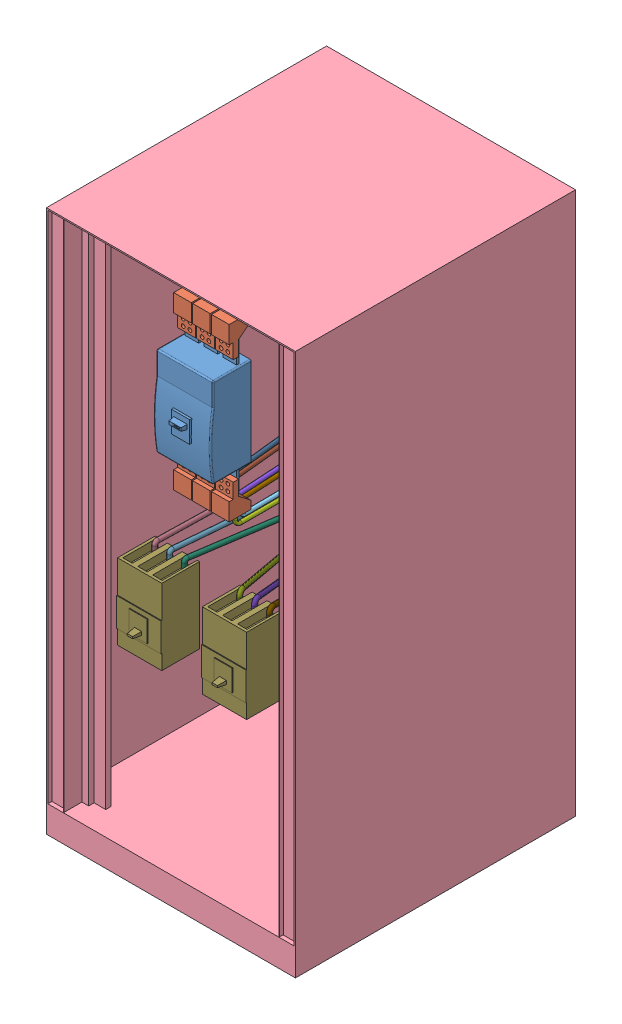
SolidWorks assembly Ensamble tablero de ditribución, configuration Predeterminado. Lengths in mm.
Overall size (920 2005 1035).
41 component instances, 19 part files, 127 mates.
Components (placement in the parent):
- INTERRUPTOR DE 1000 AMP-1: INTERRUPTOR DE 1000 AMP [Predeterminado] at (-1201.779 1141.3984 2879.7748) size (210 494 177)
- zapata interup 1000 amp-1: zapata interup 1000 amp [Predeterminado] at (-1271.779 1397.3984 2878.2748) size (65 120 80)
- zapata interup 1000 amp-2: zapata interup 1000 amp [Predeterminado] at (-1201.779 1397.3984 2878.2748) size (65 120 80)
- zapata interup 1000 amp-3: zapata interup 1000 amp [Predeterminado] at (-1131.779 1397.3984 2878.2748) size (65 120 80)
- zapata interup 1000 amp-7: zapata interup 1000 amp [Predeterminado] at (-1271.779 885.3984 2878.2748) x (-1 0 0) z (0 0 1) size (65 120 80)
- zapata interup 1000 amp-8: zapata interup 1000 amp [Predeterminado] at (-1201.779 885.3984 2878.2748) x (-1 0 0) z (0 0 1) size (65 120 80)
- zapata interup 1000 amp-9: zapata interup 1000 amp [Predeterminado] at (-1131.779 885.3984 2878.2748) x (-1 0 0) z (0 0 1) size (65 120 80)
- BARRA DE COBRE-4: BARRA DE COBRE [Predeterminado] at (-1307.279 325.3984 2071.2616) x (0 0 1) z (0 1 0) size (50.8 6 500)
- BARRA DE COBRE-5: BARRA DE COBRE [Predeterminado] at (-1201.779 825.3984 2071.2616) x (0 0 -1) z (0 -1 0) size (50.8 6 500)
- BARRA DE COBRE-6: BARRA DE COBRE [Predeterminado] at (-1096.279 825.3984 2071.2616) x (0 0 -1) z (0 -1 0) size (50.8 6 500)
- zapata interup 1000 amp-10: zapata interup 1000 amp [Predeterminado] at (-1375.279 792.8984 2105.8616) x (0 1 0) z (1 0 0) size (65 120 80)
- zapata interup 1000 amp-11: zapata interup 1000 amp [Predeterminado] at (-1269.779 792.8984 2105.8616) x (0 1 0) z (1 0 0) size (65 120 80)
- zapata interup 1000 amp-12: zapata interup 1000 amp [Predeterminado] at (-1164.279 792.8984 2105.8616) x (0 1 0) z (1 0 0) size (65 120 80)
- TABLERO DE D. 15-5-19-1: TABLERO DE D. 15-5-19 [Predeterminado] at (-1201.779 603.8984 2035.8616) size (920 2005 1035)
- Pieza5^Ensamble tablero de ditribución-1: Pieza5^Ensamble tablero de ditribución [Predeterminado] at (-1131.779 825.3984 2878.2748) x (-1 0 0) z (0 -1 0) size (20.5 735.48 26.98) (virtual)
- CABLE INTERRUP 1000-1: CABLE INTERRUP 1000 [Predeterminado] at (-1285.779 1597.3984 2894.2748) x (0.998379 0 0.056922) z (0 -1 0) size (18 18 140)
- CABLE INTERRUP 1000-2: CABLE INTERRUP 1000 [Predeterminado] at (-1257.779 1597.3984 2894.2748) x (0.733767 0 0.679401) z (0 -1 0) size (18 18 140)
- CABLE INTERRUP 1000-3: CABLE INTERRUP 1000 [Predeterminado] at (-1215.779 1597.3984 2894.2748) x (1 0 0) z (0 -1 0) size (18 18 140)
- CABLE INTERRUP 1000-4: CABLE INTERRUP 1000 [Predeterminado] at (-1187.779 1597.3984 2894.2748) x (1 0 0) z (0 -1 0) size (18 18 140)
- CABLE INTERRUP 1000-5: CABLE INTERRUP 1000 [Predeterminado] at (-1145.779 1597.3984 2894.2748) x (0.945572 0 0.325412) z (0 -1 0) size (18 18 140)
- CABLE INTERRUP 1000-6: CABLE INTERRUP 1000 [Predeterminado] at (-1117.779 1597.3984 2894.2748) x (1 0 0) z (0 -1 0) size (18 18 140)
- Pieza10^Ensamble tablero de ditribución-1: Pieza10^Ensamble tablero de ditribución [Predeterminado] at (-1131.779 825.3984 2878.2748) x (-1 0 0) z (0 -1 0) size (20.5 759.5 53.5) (virtual)
- Pieza11^Ensamble tablero de ditribución-1: Pieza11^Ensamble tablero de ditribución [Predeterminado] at (-1201.779 825.3984 2878.2748) x (-1 0 0) z (0 -1 0) size (55.99 735.82 26.98) (virtual)
- Pieza12^Ensamble tablero de ditribución-1: Pieza12^Ensamble tablero de ditribución [Predeterminado] at (-1201.779 825.3984 2878.2748) x (-1 0 0) z (0 -1 0) size (55.99 759.81 53.5) (virtual)
- Pieza13^Ensamble tablero de ditribución-1: Pieza13^Ensamble tablero de ditribución [Predeterminado] at (-1271.779 825.3984 2878.2748) x (-1 0 0) z (0 -1 0) size (91.46 736.15 26.98) (virtual)
- Pieza15^Ensamble tablero de ditribución-1: Pieza15^Ensamble tablero de ditribución [Predeterminado] at (-1271.779 825.3984 2878.2748) x (-1 0 0) z (0 -1 0) size (91.46 760.13 53.5) (virtual)
- INTERRUPTOR DE BAJA-1: INTERRUPTOR DE BAJA [Predeterminado] at (-1276.779 436.6484 2960.2748) x (0 0 1) z (-1 0 0) size (175 279.5 163.5)
- INTERRUPTOR DE BAJA-3: INTERRUPTOR DE BAJA [Predeterminado] at (-963.279 436.6484 2960.2748) x (0 0 1) z (-1 0 0) size (175 279.5 163.5)
- zapata interup 1000 amp-19: zapata interup 1000 amp [Predeterminado] at (-1375.279 607.8984 2105.8616) x (0 1 0) z (1 0 0) size (65 120 80)
- zapata interup 1000 amp-20: zapata interup 1000 amp [Predeterminado] at (-1269.779 607.8984 2105.8616) x (0 1 0) z (1 0 0) size (65 120 80)
- zapata interup 1000 amp-21: zapata interup 1000 amp [Predeterminado] at (-1164.279 607.8984 2105.8616) x (0 1 0) z (1 0 0) size (65 120 80)
- zapata interup 1000 amp-22: zapata interup 1000 amp [Predeterminado] at (-1375.279 422.8984 2105.8616) x (0 1 0) z (1 0 0) size (65 120 80)
- zapata interup 1000 amp-23: zapata interup 1000 amp [Predeterminado] at (-1269.779 422.8984 2105.8616) x (0 1 0) z (1 0 0) size (65 120 80)
- zapata interup 1000 amp-24: zapata interup 1000 amp [Predeterminado] at (-1164.279 422.8984 2105.8616) x (0 1 0) z (1 0 0) size (65 120 80)
- Pieza19^Ensamble tablero de ditribución-1: Pieza19^Ensamble tablero de ditribución [Predeterminado] at (-1276.779 546.3984 2960.2748) x (0 0 1) z (0 1 0) size (762.47 69.48 83.49) (virtual)
- Pieza21^Ensamble tablero de ditribución-1: Pieza21^Ensamble tablero de ditribución [Predeterminado] at (-1276.779 546.3984 2960.2748) x (0 0 1) z (0 1 0) (virtual)
- Pieza22^Ensamble tablero de ditribución-1: Pieza22^Ensamble tablero de ditribución [Predeterminado] at (-1276.779 546.3984 2960.2748) x (0 0 1) z (0 1 0) size (762.95 119.93 83.49) (virtual)
- Pieza23^Ensamble tablero de ditribución-1: Pieza23^Ensamble tablero de ditribución [Predeterminado] at (-1276.779 546.3984 2960.2748) x (0 0 1) z (0 1 0) size (763.44 170.34 83.49) (virtual)
- Pieza24^Ensamble tablero de ditribución-1: Pieza24^Ensamble tablero de ditribución [Predeterminado] at (-963.279 546.3984 2960.2748) x (0 0 1) z (0 1 0) size (764.75 275.58 162.29) (virtual)
- Pieza25^Ensamble tablero de ditribución-1: Pieza25^Ensamble tablero de ditribución [Predeterminado] at (-963.279 546.3984 2960.2748) x (0 0 1) z (0 1 0) size (764.38 225.22 162.22) (virtual)
- Pieza26^Ensamble tablero de ditribución-1: Pieza26^Ensamble tablero de ditribución [Predeterminado] at (-963.279 546.3984 2960.2748) x (0 0 1) z (0 1 0) size (764.02 174.83 162.16) (virtual)
Mates (geometry in assembly coordinates):
- Coincidente4: coincident anti-aligned: plane of INTERRUPTOR DE 1000 AMP-1 through (-1014.3897 1388.3984 2923.2748) normal (0 0 1); plane of zapata interup 1000 amp-1 through (-1319.279 1337.3984 2923.2748) normal (0 0 -1)
- Concéntrica1: concentric aligned: cylinder of INTERRUPTOR DE 1000 AMP-1 through (-1284.279 1352.3984 2895.4758) axis (0 0 1) radius 7; cylinder of zapata interup 1000 amp-1 through (-1284.279 1352.3984 2903.4758) axis (0 0 1) radius 7
- Coincidente5: coincident anti-aligned: plane of INTERRUPTOR DE 1000 AMP-1 through (-1014.3897 1388.3984 2923.2748) normal (0 0 1); plane of zapata interup 1000 amp-2 through (-1249.279 1337.3984 2923.2748) normal (0 0 -1)
- Concéntrica2: concentric aligned: cylinder of INTERRUPTOR DE 1000 AMP-1 through (-1189.279 1352.3984 2895.4758) axis (0 0 1) radius 7; cylinder of zapata interup 1000 amp-2 through (-1189.279 1352.3984 2903.4758) axis (0 0 1) radius 7
- Coincidente6: coincident anti-aligned: plane of INTERRUPTOR DE 1000 AMP-1 through (-1014.3897 1388.3984 2923.2748) normal (0 0 1); plane of zapata interup 1000 amp-3 through (-1179.279 1337.3984 2923.2748) normal (0 0 -1)
- Concéntrica4: concentric aligned: cylinder of INTERRUPTOR DE 1000 AMP-1 through (-1144.279 1352.3984 2895.4758) axis (0 0 1) radius 7; cylinder of zapata interup 1000 amp-3 through (-1144.279 1352.3984 2903.4758) axis (0 0 1) radius 7
- Coincidente8: coincident anti-aligned: plane of INTERRUPTOR DE 1000 AMP-1 through (-1014.3897 894.3984 2923.2748) normal (0 0 1); plane of zapata interup 1000 amp-9 through (-1084.279 945.3984 2923.2748) normal (0 0 -1)
- Ancho3: width aligned: plane of zapata interup 1000 amp-9 through (-1099.279 945.3984 2958.2748) normal (1 0 0); plane of zapata interup 1000 amp-9 through (-1164.279 945.3984 2958.2748) normal (-1 0 0); plane of INTERRUPTOR DE 1000 AMP-1 through (-1106.779 976.3984 2830.871) normal (1 0 0); plane of INTERRUPTOR DE 1000 AMP-1 through (-1156.779 976.3984 2830.871) normal (-1 0 0)
- Concéntrica5: concentric aligned: cylinder of INTERRUPTOR DE 1000 AMP-1 through (-1119.279 906.3984 2894.6673) axis (0 0 1) radius 7; cylinder of zapata interup 1000 amp-9 through (-1119.279 906.3984 2903.4758) axis (0 0 1) radius 7
- Coincidente10: coincident anti-aligned: plane of INTERRUPTOR DE 1000 AMP-1 through (-1014.3897 894.3984 2923.2748) normal (0 0 1); plane of zapata interup 1000 amp-8 through (-1154.279 945.3984 2923.2748) normal (0 0 -1)
- Ancho4: width aligned: plane of zapata interup 1000 amp-8 through (-1169.279 945.3984 2958.2748) normal (1 0 0); plane of zapata interup 1000 amp-8 through (-1234.279 945.3984 2958.2748) normal (-1 0 0); plane of INTERRUPTOR DE 1000 AMP-1 through (-1176.779 976.3984 2830.871) normal (1 0 0); plane of INTERRUPTOR DE 1000 AMP-1 through (-1226.779 976.3984 2830.871) normal (-1 0 0)
- Coincidente11: coincident anti-aligned: plane of INTERRUPTOR DE 1000 AMP-1 through (-1014.3897 894.3984 2923.2748) normal (0 0 1); plane of zapata interup 1000 amp-7 through (-1224.279 945.3984 2923.2748) normal (0 0 -1)
- Ancho5: width aligned: plane of zapata interup 1000 amp-7 through (-1304.279 945.3984 2958.2748) normal (-1 0 0); plane of zapata interup 1000 amp-7 through (-1239.279 945.3984 2958.2748) normal (1 0 0); plane of INTERRUPTOR DE 1000 AMP-1 through (-1296.779 976.3984 2830.871) normal (-1 0 0); plane of INTERRUPTOR DE 1000 AMP-1 through (-1246.779 976.3984 2830.871) normal (1 0 0)
- Concéntrica6: concentric aligned: cylinder of INTERRUPTOR DE 1000 AMP-1 through (-1214.279 906.3984 2894.6673) axis (0 0 1) radius 7; cylinder of zapata interup 1000 amp-8 through (-1214.279 906.3984 2903.4758) axis (0 0 1) radius 7
- Concéntrica7: concentric aligned: cylinder of INTERRUPTOR DE 1000 AMP-1 through (-1259.279 906.3984 2894.6673) axis (0 0 1) radius 7; cylinder of zapata interup 1000 amp-7 through (-1259.279 906.3984 2903.4758) axis (0 0 1) radius 7
- Coincidente21: coincident aligned: plane of BARRA DE COBRE-4 through (-1304.279 825.3984 2045.8616) normal (0 0 -1); plane of BARRA DE COBRE-5 through (-1198.779 325.3984 2045.8616) normal (0 0 -1)
- Coincidente22: coincident anti-aligned: plane of zapata interup 1000 amp-7 through (-1239.279 825.3984 2958.2748) normal (0 -1 0); plane of BARRA DE COBRE-4 through (-1307.279 825.3984 2071.2616) normal (0 1 0)
- Coincidente23: coincident aligned: plane of BARRA DE COBRE-4 through (-1307.279 825.3984 2071.2616) normal (0 1 0); plane of BARRA DE COBRE-5 through (-1201.779 825.3984 2071.2616) normal (0 1 0)
- Coincidente24: coincident aligned: plane of BARRA DE COBRE-5 through (-1198.779 325.3984 2045.8616) normal (0 0 -1); plane of BARRA DE COBRE-6 through (-1093.279 325.3984 2045.8616) normal (0 0 -1)
- Coincidente25: coincident aligned: plane of BARRA DE COBRE-5 through (-1201.779 825.3984 2071.2616) normal (0 1 0); plane of BARRA DE COBRE-6 through (-1096.279 825.3984 2071.2616) normal (0 1 0)
- Coincidente26: coincident anti-aligned: plane of BARRA DE COBRE-4 through (-1310.279 825.3984 2045.8616) normal (-1 0 0); plane of zapata interup 1000 amp-10 through (-1310.279 745.3984 2100.8616) normal (1 0 0)
- Coincidente27: coincident aligned: plane of BARRA DE COBRE-4 through (-1304.279 825.3984 2045.8616) normal (0 0 -1); plane of zapata interup 1000 amp-10 through (-1295.279 760.3984 2045.8616) normal (0 0 -1)
- Coincidente28: coincident aligned: plane of BARRA DE COBRE-4 through (-1307.279 825.3984 2071.2616) normal (0 1 0); plane of zapata interup 1000 amp-10 through (-1295.279 825.3984 2045.8616) normal (0 1 0)
- Coincidente29: coincident anti-aligned: plane of zapata interup 1000 amp-7 through (-1304.279 945.3984 2958.2748) normal (-1 0 0); plane of BARRA DE COBRE-4 through (-1304.279 825.3984 2045.8616) normal (1 0 0)
- Coincidente30: coincident anti-aligned: plane of zapata interup 1000 amp-9 through (-1099.279 945.3984 2958.2748) normal (1 0 0); plane of BARRA DE COBRE-6 through (-1099.279 325.3984 2096.6616) normal (-1 0 0)
- Ancho12: width anti-aligned: plane of zapata interup 1000 amp-8 through (-1169.279 945.3984 2958.2748) normal (1 0 0); plane of zapata interup 1000 amp-8 through (-1234.279 945.3984 2958.2748) normal (-1 0 0); plane of BARRA DE COBRE-5 through (-1204.779 325.3984 2096.6616) normal (-1 0 0); plane of BARRA DE COBRE-5 through (-1198.779 325.3984 2096.6616) normal (1 0 0)
- Coincidente31: coincident anti-aligned: plane of BARRA DE COBRE-5 through (-1204.779 325.3984 2096.6616) normal (-1 0 0); plane of zapata interup 1000 amp-11 through (-1204.779 745.3984 2100.8616) normal (1 0 0)
- Coincidente32: coincident aligned: plane of BARRA DE COBRE-5 through (-1201.779 825.3984 2071.2616) normal (0 1 0); plane of zapata interup 1000 amp-11 through (-1189.779 825.3984 2045.8616) normal (0 1 0)
- Coincidente33: coincident aligned: plane of BARRA DE COBRE-5 through (-1198.779 325.3984 2045.8616) normal (0 0 -1); plane of zapata interup 1000 amp-11 through (-1189.779 760.3984 2045.8616) normal (0 0 -1)
- Coincidente34: coincident anti-aligned: plane of BARRA DE COBRE-6 through (-1099.279 325.3984 2096.6616) normal (-1 0 0); plane of zapata interup 1000 amp-12 through (-1099.279 745.3984 2100.8616) normal (1 0 0)
- Coincidente35: coincident aligned: plane of BARRA DE COBRE-6 through (-1093.279 325.3984 2045.8616) normal (0 0 -1); plane of zapata interup 1000 amp-12 through (-1084.279 760.3984 2045.8616) normal (0 0 -1)
- Coincidente36: coincident aligned: plane of BARRA DE COBRE-6 through (-1096.279 825.3984 2071.2616) normal (0 1 0); plane of zapata interup 1000 amp-12 through (-1084.279 825.3984 2045.8616) normal (0 1 0)
- Coincidente37: coincident aligned: plane of INTERRUPTOR DE 1000 AMP-1 through (-1201.779 1141.3984 3055.7748) normal (0 0 1); plane of TABLERO DE D. 15-5-19-1 through (-1601.779 1679.1188 3055.7748) normal (0 0 1)
- Ancho13: width aligned: plane of TABLERO DE D. 15-5-19-1 through (-1661.779 -398.6016 3070.8616) normal (-1 0 0); plane of TABLERO DE D. 15-5-19-1 through (-741.779 -398.6016 3070.8616) normal (1 0 0); plane of INTERRUPTOR DE 1000 AMP-1 through (-1306.779 976.3984 3029.7748) normal (-1 0 0); plane of INTERRUPTOR DE 1000 AMP-1 through (-1096.779 976.3984 3029.7748) normal (1 0 0)
- Distancia4: distance = 300 mm aligned: plane of TABLERO DE D. 15-5-19-1 through (-1661.779 1606.3984 3070.8616) normal (0 1 0); plane of INTERRUPTOR DE 1000 AMP-1 through (-1306.779 1306.3984 3029.7748) normal (0 1 0)
- Coincidente39: coincident anti-aligned: plane of BARRA DE COBRE-6 through (-1093.279 325.3984 2045.8616) normal (0 0 -1); plane of TABLERO DE D. 15-5-19-1 through (-1201.779 603.8984 2045.8616) normal (0 0 1)
- EnPosición3: in place: plane of zapata interup 1000 amp-9 through (-1099.279 825.3984 2958.2748) normal (0 -1 0); plane of ? through (0 825.3984 0) normal (0 -1 0); moOrthogonalPlaneRef_w of zapata interup 1000 amp-9 through (-1099.279 825.3984 2958.2748) normal (0 -1 0); unknown of ?; plane of zapata interup 1000 amp-9 through (-1099.279 825.3984 2958.2748) normal (0 -1 0); line of ? through (-55 0 825.3984) axis (0 -1 0); plane of zapata interup 1000 amp-9 through (-1099.279 825.3984 2958.2748) normal (0 -1 0); unknown of ?
- Coincidente53: coincident aligned: plane of zapata interup 1000 amp-9; plane of Pieza5^Ensamble tablero de ditribución-1
- Coincidente54: coincident aligned: moOrthogonalPlaneRef_w of zapata interup 1000 amp-9 through (-1131.779 825.3984 2878.2748) normal (0 0 -1); plane of Pieza5^Ensamble tablero de ditribución-1
- Coincidente55: coincident anti-aligned: moOrthogonalPlaneRef_w of zapata interup 1000 amp-9 through (-1131.779 825.3984 2878.2748) normal (1 0 0); plane of Pieza5^Ensamble tablero de ditribución-1
- Concéntrica8: concentric aligned: cylinder of zapata interup 1000 amp-1 through (-1285.779 1447.3984 2894.2748) axis (0 1 0) radius 7; cylinder of CABLE INTERRUP 1000-1 through (-1285.779 1457.3984 2894.2748) axis (0 1 0) radius 9
- Paralelo1: parallel aligned: plane of INTERRUPTOR DE 1000 AMP-1 through (-1296.779 1388.3984 2830.871) normal (-1 0 0); plane of zapata interup 1000 amp-1 through (-1304.279 1337.3984 2958.2748) normal (-1 0 0)
- Coincidente65: coincident anti-aligned: plane of zapata interup 1000 amp-1 through (-1304.279 1457.3984 2958.2748) normal (0 1 0); plane of CABLE INTERRUP 1000-1 through (-1285.779 1457.3984 2894.2748) normal (0 -1 0)
- Concéntrica9: concentric aligned: cylinder of zapata interup 1000 amp-1 through (-1257.779 1447.3984 2894.2748) axis (0 1 0) radius 7; cylinder of CABLE INTERRUP 1000-2 through (-1257.779 1457.3984 2894.2748) axis (0 1 0) radius 9
- Coincidente66: coincident anti-aligned: plane of zapata interup 1000 amp-1 through (-1304.279 1457.3984 2958.2748) normal (0 1 0); plane of CABLE INTERRUP 1000-2 through (-1257.779 1457.3984 2894.2748) normal (0 -1 0)
- Concéntrica10: concentric aligned: cylinder of zapata interup 1000 amp-2 through (-1215.779 1447.3984 2894.2748) axis (0 1 0) radius 7; cylinder of CABLE INTERRUP 1000-3 through (-1215.779 1457.3984 2894.2748) axis (0 1 0) radius 9
- Coincidente67: coincident anti-aligned: plane of zapata interup 1000 amp-2 through (-1234.279 1457.3984 2958.2748) normal (0 1 0); plane of CABLE INTERRUP 1000-3 through (-1215.779 1457.3984 2894.2748) normal (0 -1 0)
- Concéntrica11: concentric aligned: cylinder of zapata interup 1000 amp-2 through (-1187.779 1447.3984 2894.2748) axis (0 1 0) radius 7; cylinder of CABLE INTERRUP 1000-4 through (-1187.779 1457.3984 2894.2748) axis (0 1 0) radius 9
- Coincidente68: coincident anti-aligned: plane of zapata interup 1000 amp-2 through (-1234.279 1457.3984 2958.2748) normal (0 1 0); plane of CABLE INTERRUP 1000-4 through (-1187.779 1457.3984 2894.2748) normal (0 -1 0)
- Concéntrica12: concentric aligned: cylinder of zapata interup 1000 amp-3 through (-1145.779 1447.3984 2894.2748) axis (0 1 0) radius 7; cylinder of CABLE INTERRUP 1000-5 through (-1145.779 1457.3984 2894.2748) axis (0 1 0) radius 9
- Paralelo2: parallel aligned: plane of INTERRUPTOR DE 1000 AMP-1 through (-1106.779 1306.3984 2830.871) normal (1 0 0); plane of zapata interup 1000 amp-3 through (-1099.279 1337.3984 2958.2748) normal (1 0 0)
- Coincidente69: coincident anti-aligned: plane of zapata interup 1000 amp-3 through (-1164.279 1457.3984 2958.2748) normal (0 1 0); plane of CABLE INTERRUP 1000-5 through (-1145.779 1457.3984 2894.2748) normal (0 -1 0)
- Concéntrica13: concentric aligned: cylinder of zapata interup 1000 amp-3 through (-1117.779 1447.3984 2894.2748) axis (0 1 0) radius 7; cylinder of CABLE INTERRUP 1000-6 through (-1117.779 1457.3984 2894.2748) axis (0 1 0) radius 9
- Coincidente70: coincident anti-aligned: plane of zapata interup 1000 amp-3 through (-1164.279 1457.3984 2958.2748) normal (0 1 0); plane of CABLE INTERRUP 1000-6 through (-1117.779 1457.3984 2894.2748) normal (0 -1 0)
- EnPosición7: in place: plane of zapata interup 1000 amp-9 through (-1099.279 825.3984 2958.2748) normal (0 -1 0); plane of ? through (0 825.3984 0) normal (0 -1 0); plane of zapata interup 1000 amp-9 through (-1099.279 825.3984 2958.2748) normal (0 -1 0); unknown of ?; plane of zapata interup 1000 amp-9 through (-1099.279 825.3984 2958.2748) normal (0 -1 0); line of ? through (-55 0 825.3984) axis (0 -1 0); plane of zapata interup 1000 amp-9 through (-1099.279 825.3984 2958.2748) normal (0 -1 0); unknown of ?
- Coincidente71: coincident aligned: plane of zapata interup 1000 amp-9; plane of Pieza10^Ensamble tablero de ditribución-1
- Coincidente72: coincident aligned: moOrthogonalPlaneRef_w of zapata interup 1000 amp-9 through (-1131.779 825.3984 2878.2748) normal (0 0 -1); plane of Pieza10^Ensamble tablero de ditribución-1
- Coincidente73: coincident anti-aligned: moOrthogonalPlaneRef_w of zapata interup 1000 amp-9 through (-1131.779 825.3984 2878.2748) normal (1 0 0); plane of Pieza10^Ensamble tablero de ditribución-1
- EnPosición8: in place: plane of zapata interup 1000 amp-8 through (-1169.279 825.3984 2958.2748) normal (0 -1 0); plane of ? through (0 825.3984 0) normal (0 -1 0); plane of zapata interup 1000 amp-8 through (-1169.279 825.3984 2958.2748) normal (0 -1 0); unknown of ?; plane of zapata interup 1000 amp-8 through (-1169.279 825.3984 2958.2748) normal (0 -1 0); line of ? through (-55 0 825.3984) axis (0 -1 0); plane of zapata interup 1000 amp-8 through (-1169.279 825.3984 2958.2748) normal (0 -1 0); unknown of ?
- Coincidente74: coincident aligned: plane of zapata interup 1000 amp-8; plane of Pieza11^Ensamble tablero de ditribución-1
- Coincidente75: coincident aligned: moOrthogonalPlaneRef_w of zapata interup 1000 amp-8 through (-1201.779 825.3984 2878.2748) normal (0 0 -1); plane of Pieza11^Ensamble tablero de ditribución-1
- Coincidente76: coincident anti-aligned: moOrthogonalPlaneRef_w of zapata interup 1000 amp-8 through (-1201.779 825.3984 2878.2748) normal (1 0 0); plane of Pieza11^Ensamble tablero de ditribución-1
- EnPosición9: in place: plane of zapata interup 1000 amp-8 through (-1169.279 825.3984 2958.2748) normal (0 -1 0); plane of ? through (0 825.3984 0) normal (0 -1 0); plane of zapata interup 1000 amp-8 through (-1169.279 825.3984 2958.2748) normal (0 -1 0); unknown of ?; plane of zapata interup 1000 amp-8 through (-1169.279 825.3984 2958.2748) normal (0 -1 0); line of ? through (-55 0 825.3984) axis (0 -1 0); plane of zapata interup 1000 amp-8 through (-1169.279 825.3984 2958.2748) normal (0 -1 0); unknown of ?
- Coincidente77: coincident aligned: plane of zapata interup 1000 amp-8; plane of Pieza12^Ensamble tablero de ditribución-1
- Coincidente78: coincident aligned: moOrthogonalPlaneRef_w of zapata interup 1000 amp-8 through (-1201.779 825.3984 2878.2748) normal (0 0 -1); plane of Pieza12^Ensamble tablero de ditribución-1
- Coincidente79: coincident anti-aligned: moOrthogonalPlaneRef_w of zapata interup 1000 amp-8 through (-1201.779 825.3984 2878.2748) normal (1 0 0); plane of Pieza12^Ensamble tablero de ditribución-1
- EnPosición10: in place: plane of zapata interup 1000 amp-7 through (-1239.279 825.3984 2958.2748) normal (0 -1 0); plane of ? through (0 825.3984 0) normal (0 -1 0); plane of zapata interup 1000 amp-7 through (-1239.279 825.3984 2958.2748) normal (0 -1 0); unknown of ?; plane of zapata interup 1000 amp-7 through (-1239.279 825.3984 2958.2748) normal (0 -1 0); line of ? through (-55 0 825.3984) axis (0 -1 0); plane of zapata interup 1000 amp-7 through (-1239.279 825.3984 2958.2748) normal (0 -1 0); unknown of ?
- Coincidente80: coincident aligned: plane of zapata interup 1000 amp-7; plane of Pieza13^Ensamble tablero de ditribución-1
- Coincidente81: coincident aligned: moOrthogonalPlaneRef_w of zapata interup 1000 amp-7 through (-1271.779 825.3984 2878.2748) normal (0 0 -1); plane of Pieza13^Ensamble tablero de ditribución-1
- Coincidente82: coincident anti-aligned: moOrthogonalPlaneRef_w of zapata interup 1000 amp-7 through (-1271.779 825.3984 2878.2748) normal (1 0 0); plane of Pieza13^Ensamble tablero de ditribución-1
- EnPosición12: in place: plane of zapata interup 1000 amp-7 through (-1239.279 825.3984 2958.2748) normal (0 -1 0); plane of ? through (0 825.3984 0) normal (0 -1 0); plane of zapata interup 1000 amp-7 through (-1239.279 825.3984 2958.2748) normal (0 -1 0); unknown of ?; plane of zapata interup 1000 amp-7 through (-1239.279 825.3984 2958.2748) normal (0 -1 0); line of ? through (-55 0 825.3984) axis (0 -1 0); plane of zapata interup 1000 amp-7 through (-1239.279 825.3984 2958.2748) normal (0 -1 0); unknown of ?
- Coincidente86: coincident aligned: plane of zapata interup 1000 amp-7; plane of Pieza15^Ensamble tablero de ditribución-1
- Coincidente87: coincident aligned: moOrthogonalPlaneRef_w of zapata interup 1000 amp-7 through (-1271.779 825.3984 2878.2748) normal (0 0 -1); plane of Pieza15^Ensamble tablero de ditribución-1
- Coincidente88: coincident anti-aligned: moOrthogonalPlaneRef_w of zapata interup 1000 amp-7 through (-1271.779 825.3984 2878.2748) normal (1 0 0); plane of Pieza15^Ensamble tablero de ditribución-1
- Coincidente71: coincident aligned: plane of INTERRUPTOR DE 1000 AMP-1 through (-1201.779 1141.3984 3035.7748) normal (0 0 1); plane of INTERRUPTOR DE BAJA-1 through (-1276.779 436.6484 3035.7748) normal (0 0 1)
- Distancia5: distance = 400 mm anti-aligned: plane of INTERRUPTOR DE 1000 AMP-1 through (-1306.779 976.3984 3029.7748) normal (0 -1 0); plane of INTERRUPTOR DE BAJA-1 through (-1440.279 576.3984 2890.7748) normal (0 1 0)
- Distancia6: distance = 400 mm anti-aligned: plane of INTERRUPTOR DE 1000 AMP-1 through (-1306.779 976.3984 3029.7748) normal (0 -1 0); plane of INTERRUPTOR DE BAJA-3 through (-1126.779 576.3984 2890.7748) normal (0 1 0)
- Coincidente75: coincident aligned: plane of INTERRUPTOR DE BAJA-1 through (-1276.779 436.6484 3035.7748) normal (0 0 1); plane of INTERRUPTOR DE BAJA-3 through (-963.279 436.6484 3035.7748) normal (0 0 1)
- Distancia7: distance = 150 mm anti-aligned: plane of INTERRUPTOR DE BAJA-1 through (-1276.779 436.6484 2960.2748) normal (1 0 0); plane of INTERRUPTOR DE BAJA-3 through (-1126.779 436.6484 2960.2748) normal (-1 0 0)
- Ancho14: width anti-aligned: plane of TABLERO DE D. 15-5-19-1 through (-1531.279 1728.1511 2962.8616) normal (1 0 0); plane of TABLERO DE D. 15-5-19-1 through (-872.279 1728.1511 2962.8616) normal (-1 0 0); plane of INTERRUPTOR DE BAJA-1 through (-1440.279 436.6484 2960.2748) normal (-1 0 0); plane of INTERRUPTOR DE BAJA-3 through (-963.279 436.6484 2960.2748) normal (1 0 0)
- Distancia8: distance = 120 mm anti-aligned: plane of zapata interup 1000 amp-10 through (-1295.279 760.3984 2045.8616) normal (0 -1 0); plane of zapata interup 1000 amp-19 through (-1295.279 640.3984 2045.8616) normal (0 1 0)
- Coincidente78: coincident anti-aligned: plane of BARRA DE COBRE-4 through (-1310.279 825.3984 2045.8616) normal (-1 0 0); plane of zapata interup 1000 amp-19 through (-1310.279 560.3984 2100.8616) normal (1 0 0)
- Coincidente79: coincident aligned: plane of BARRA DE COBRE-4 through (-1304.279 825.3984 2045.8616) normal (0 0 -1); plane of zapata interup 1000 amp-19 through (-1295.279 575.3984 2045.8616) normal (0 0 -1)
- Coincidente80: coincident aligned: plane of zapata interup 1000 amp-19 through (-1295.279 640.3984 2045.8616) normal (0 1 0); plane of zapata interup 1000 amp-20 through (-1189.779 640.3984 2045.8616) normal (0 1 0)
- Coincidente81: coincident anti-aligned: plane of BARRA DE COBRE-5 through (-1204.779 325.3984 2096.6616) normal (-1 0 0); plane of zapata interup 1000 amp-20 through (-1204.779 560.3984 2100.8616) normal (1 0 0)
- Coincidente82: coincident aligned: plane of BARRA DE COBRE-5 through (-1198.779 325.3984 2045.8616) normal (0 0 -1); plane of zapata interup 1000 amp-20 through (-1189.779 575.3984 2045.8616) normal (0 0 -1)
- Coincidente83: coincident aligned: plane of zapata interup 1000 amp-20 through (-1189.779 640.3984 2045.8616) normal (0 1 0); plane of zapata interup 1000 amp-21 through (-1084.279 640.3984 2045.8616) normal (0 1 0)
- Coincidente84: coincident anti-aligned: plane of BARRA DE COBRE-6 through (-1099.279 325.3984 2096.6616) normal (-1 0 0); plane of zapata interup 1000 amp-21 through (-1099.279 560.3984 2100.8616) normal (1 0 0)
- Coincidente85: coincident aligned: plane of BARRA DE COBRE-6 through (-1093.279 325.3984 2045.8616) normal (0 0 -1); plane of zapata interup 1000 amp-21 through (-1084.279 575.3984 2045.8616) normal (0 0 -1)
- Distancia9: distance = 120 mm anti-aligned: plane of zapata interup 1000 amp-19 through (-1295.279 575.3984 2045.8616) normal (0 -1 0); plane of zapata interup 1000 amp-22 through (-1295.279 455.3984 2045.8616) normal (0 1 0)
- Coincidente87: coincident anti-aligned: plane of BARRA DE COBRE-4 through (-1310.279 825.3984 2045.8616) normal (-1 0 0); plane of zapata interup 1000 amp-22 through (-1310.279 375.3984 2100.8616) normal (1 0 0)
- Coincidente88: coincident aligned: plane of BARRA DE COBRE-4 through (-1304.279 825.3984 2045.8616) normal (0 0 -1); plane of zapata interup 1000 amp-22 through (-1295.279 390.3984 2045.8616) normal (0 0 -1)
- Coincidente89: coincident aligned: plane of zapata interup 1000 amp-22 through (-1295.279 455.3984 2045.8616) normal (0 1 0); plane of zapata interup 1000 amp-23 through (-1189.779 455.3984 2045.8616) normal (0 1 0)
- Coincidente90: coincident anti-aligned: plane of BARRA DE COBRE-5 through (-1204.779 325.3984 2096.6616) normal (-1 0 0); plane of zapata interup 1000 amp-23 through (-1204.779 375.3984 2100.8616) normal (1 0 0)
- Coincidente91: coincident aligned: plane of BARRA DE COBRE-5 through (-1198.779 325.3984 2045.8616) normal (0 0 -1); plane of zapata interup 1000 amp-23 through (-1189.779 390.3984 2045.8616) normal (0 0 -1)
- Coincidente92: coincident aligned: plane of zapata interup 1000 amp-22 through (-1295.279 455.3984 2045.8616) normal (0 1 0); plane of zapata interup 1000 amp-24 through (-1084.279 455.3984 2045.8616) normal (0 1 0)
- Coincidente93: coincident anti-aligned: plane of BARRA DE COBRE-6 through (-1099.279 325.3984 2096.6616) normal (-1 0 0); plane of zapata interup 1000 amp-24 through (-1099.279 375.3984 2100.8616) normal (1 0 0)
- Coincidente94: coincident anti-aligned: plane of BARRA DE COBRE-6 through (-1099.279 325.3984 2096.6616) normal (-1 0 0); plane of zapata interup 1000 amp-24 through (-1099.279 375.3984 2100.8616) normal (1 0 0)
- Coincidente95: coincident aligned: plane of BARRA DE COBRE-6 through (-1093.279 325.3984 2045.8616) normal (0 0 -1); plane of zapata interup 1000 amp-24 through (-1084.279 390.3984 2045.8616) normal (0 0 -1)
- EnPosición15: in place: plane of INTERRUPTOR DE BAJA-1 through (-1276.779 546.3984 2960.2748) normal (0 1 0); plane of ? through (0 546.3984 0) normal (0 1 0); plane of INTERRUPTOR DE BAJA-1 through (-1276.779 546.3984 2960.2748) normal (0 1 0); plane of ? through (0 546.3984 0) normal (0 0 -1); plane of INTERRUPTOR DE BAJA-1 through (-1276.779 546.3984 2960.2748) normal (0 1 0); unknown of ?; plane of INTERRUPTOR DE BAJA-1 through (-1276.779 546.3984 2960.2748) normal (0 1 0); unknown of ?
- Coincidente102: coincident aligned: plane of INTERRUPTOR DE BAJA-1; plane of Pieza19^Ensamble tablero de ditribución-1
- Coincidente103: coincident aligned: moOrthogonalPlaneRef_w of INTERRUPTOR DE BAJA-1 through (-1276.779 546.3984 2960.2748) normal (1 0 0); plane of Pieza19^Ensamble tablero de ditribución-1
- Coincidente104: coincident anti-aligned: moOrthogonalPlaneRef_w of INTERRUPTOR DE BAJA-1 through (-1276.779 546.3984 2960.2748) normal (0 0 -1); plane of Pieza19^Ensamble tablero de ditribución-1
- EnPosición17: in place: plane of INTERRUPTOR DE BAJA-1 through (-1276.779 546.3984 2960.2748) normal (0 1 0); plane of ? through (0 546.3984 0) normal (0 1 0); plane of INTERRUPTOR DE BAJA-1 through (-1276.779 546.3984 2960.2748) normal (0 1 0); plane of ? through (0 546.3984 0) normal (0 0 -1); plane of INTERRUPTOR DE BAJA-1 through (-1276.779 546.3984 2960.2748) normal (0 1 0); unknown of ?; plane of INTERRUPTOR DE BAJA-1 through (-1276.779 546.3984 2960.2748) normal (0 1 0); unknown of ?
- Coincidente108: coincident aligned: plane of INTERRUPTOR DE BAJA-1; plane of Pieza21^Ensamble tablero de ditribución-1
- Coincidente109: coincident aligned: moOrthogonalPlaneRef_w of INTERRUPTOR DE BAJA-1 through (-1276.779 546.3984 2960.2748) normal (1 0 0); plane of Pieza21^Ensamble tablero de ditribución-1
- Coincidente110: coincident anti-aligned: moOrthogonalPlaneRef_w of INTERRUPTOR DE BAJA-1 through (-1276.779 546.3984 2960.2748) normal (0 0 -1); plane of Pieza21^Ensamble tablero de ditribución-1
- EnPosición18: in place: plane of INTERRUPTOR DE BAJA-1 through (-1276.779 546.3984 2960.2748) normal (0 1 0); plane of ? through (0 546.3984 0) normal (0 1 0); plane of INTERRUPTOR DE BAJA-1 through (-1276.779 546.3984 2960.2748) normal (0 1 0); plane of ? through (0 546.3984 0) normal (0 0 -1); plane of INTERRUPTOR DE BAJA-1 through (-1276.779 546.3984 2960.2748) normal (0 1 0); unknown of ?; plane of INTERRUPTOR DE BAJA-1 through (-1276.779 546.3984 2960.2748) normal (0 1 0); unknown of ?
- Coincidente96: coincident aligned: plane of INTERRUPTOR DE BAJA-1; plane of Pieza22^Ensamble tablero de ditribución-1
- Coincidente97: coincident aligned: moOrthogonalPlaneRef_w of INTERRUPTOR DE BAJA-1 through (-1276.779 546.3984 2960.2748) normal (1 0 0); plane of Pieza22^Ensamble tablero de ditribución-1
- Coincidente98: coincident anti-aligned: moOrthogonalPlaneRef_w of INTERRUPTOR DE BAJA-1 through (-1276.779 546.3984 2960.2748) normal (0 0 -1); plane of Pieza22^Ensamble tablero de ditribución-1
- EnPosición19: in place: plane of INTERRUPTOR DE BAJA-1 through (-1276.779 546.3984 2960.2748) normal (0 1 0); plane of ? through (0 546.3984 0) normal (0 1 0); plane of INTERRUPTOR DE BAJA-1 through (-1276.779 546.3984 2960.2748) normal (0 1 0); plane of ? through (0 546.3984 0) normal (0 0 -1); plane of INTERRUPTOR DE BAJA-1 through (-1276.779 546.3984 2960.2748) normal (0 1 0); unknown of ?; plane of INTERRUPTOR DE BAJA-1 through (-1276.779 546.3984 2960.2748) normal (0 1 0); unknown of ?
- Coincidente99: coincident aligned: plane of INTERRUPTOR DE BAJA-1; plane of Pieza23^Ensamble tablero de ditribución-1
- Coincidente100: coincident aligned: moOrthogonalPlaneRef_w of INTERRUPTOR DE BAJA-1 through (-1276.779 546.3984 2960.2748) normal (1 0 0); plane of Pieza23^Ensamble tablero de ditribución-1
- Coincidente101: coincident anti-aligned: moOrthogonalPlaneRef_w of INTERRUPTOR DE BAJA-1 through (-1276.779 546.3984 2960.2748) normal (0 0 -1); plane of Pieza23^Ensamble tablero de ditribución-1
- EnPosición20: in place: plane of INTERRUPTOR DE BAJA-3 through (-963.279 546.3984 2960.2748) normal (0 1 0); plane of ? through (0 546.3984 0) normal (0 1 0); plane of INTERRUPTOR DE BAJA-3 through (-963.279 546.3984 2960.2748) normal (0 1 0); plane of ? through (0 546.3984 0) normal (0 0 -1); plane of INTERRUPTOR DE BAJA-3 through (-963.279 546.3984 2960.2748) normal (0 1 0); line of ? through (-55 0 546.3984) axis (0 1 0); plane of INTERRUPTOR DE BAJA-3 through (-963.279 546.3984 2960.2748) normal (0 1 0); unknown of ?
- Coincidente102: coincident aligned: plane of INTERRUPTOR DE BAJA-3; plane of Pieza24^Ensamble tablero de ditribución-1
- Coincidente103: coincident aligned: moOrthogonalPlaneRef_w of INTERRUPTOR DE BAJA-3 through (-963.279 546.3984 2960.2748) normal (1 0 0); plane of Pieza24^Ensamble tablero de ditribución-1
- Coincidente104: coincident anti-aligned: moOrthogonalPlaneRef_w of INTERRUPTOR DE BAJA-3 through (-963.279 546.3984 2960.2748) normal (0 0 -1); plane of Pieza24^Ensamble tablero de ditribución-1
- EnPosición21: in place: plane of INTERRUPTOR DE BAJA-3 through (-963.279 546.3984 2960.2748) normal (0 1 0); plane of ? through (0 546.3984 0) normal (0 1 0); plane of INTERRUPTOR DE BAJA-3 through (-963.279 546.3984 2960.2748) normal (0 1 0); plane of ? through (0 546.3984 0) normal (0 0 -1); plane of INTERRUPTOR DE BAJA-3 through (-963.279 546.3984 2960.2748) normal (0 1 0); line of ? through (-55 0 546.3984) axis (0 1 0); plane of INTERRUPTOR DE BAJA-3 through (-963.279 546.3984 2960.2748) normal (0 1 0); unknown of ?
- Coincidente105: coincident aligned: plane of INTERRUPTOR DE BAJA-3; plane of Pieza25^Ensamble tablero de ditribución-1
- Coincidente106: coincident aligned: moOrthogonalPlaneRef_w of INTERRUPTOR DE BAJA-3 through (-963.279 546.3984 2960.2748) normal (1 0 0); plane of Pieza25^Ensamble tablero de ditribución-1
- Coincidente107: coincident anti-aligned: moOrthogonalPlaneRef_w of INTERRUPTOR DE BAJA-3 through (-963.279 546.3984 2960.2748) normal (0 0 -1); plane of Pieza25^Ensamble tablero de ditribución-1
- EnPosición22: in place: plane of INTERRUPTOR DE BAJA-3 through (-963.279 546.3984 2960.2748) normal (0 1 0); plane of ? through (0 546.3984 0) normal (0 1 0); plane of INTERRUPTOR DE BAJA-3 through (-963.279 546.3984 2960.2748) normal (0 1 0); plane of ? through (0 546.3984 0) normal (0 0 -1); plane of INTERRUPTOR DE BAJA-3 through (-963.279 546.3984 2960.2748) normal (0 1 0); line of ? through (-55 0 546.3984) axis (0 1 0); plane of INTERRUPTOR DE BAJA-3 through (-963.279 546.3984 2960.2748) normal (0 1 0); unknown of ?
- Coincidente108: coincident aligned: plane of INTERRUPTOR DE BAJA-3; plane of Pieza26^Ensamble tablero de ditribución-1
- Coincidente109: coincident aligned: moOrthogonalPlaneRef_w of INTERRUPTOR DE BAJA-3 through (-963.279 546.3984 2960.2748) normal (1 0 0); plane of Pieza26^Ensamble tablero de ditribución-1
- Coincidente110: coincident anti-aligned: moOrthogonalPlaneRef_w of INTERRUPTOR DE BAJA-3 through (-963.279 546.3984 2960.2748) normal (0 0 -1); plane of Pieza26^Ensamble tablero de ditribución-1
